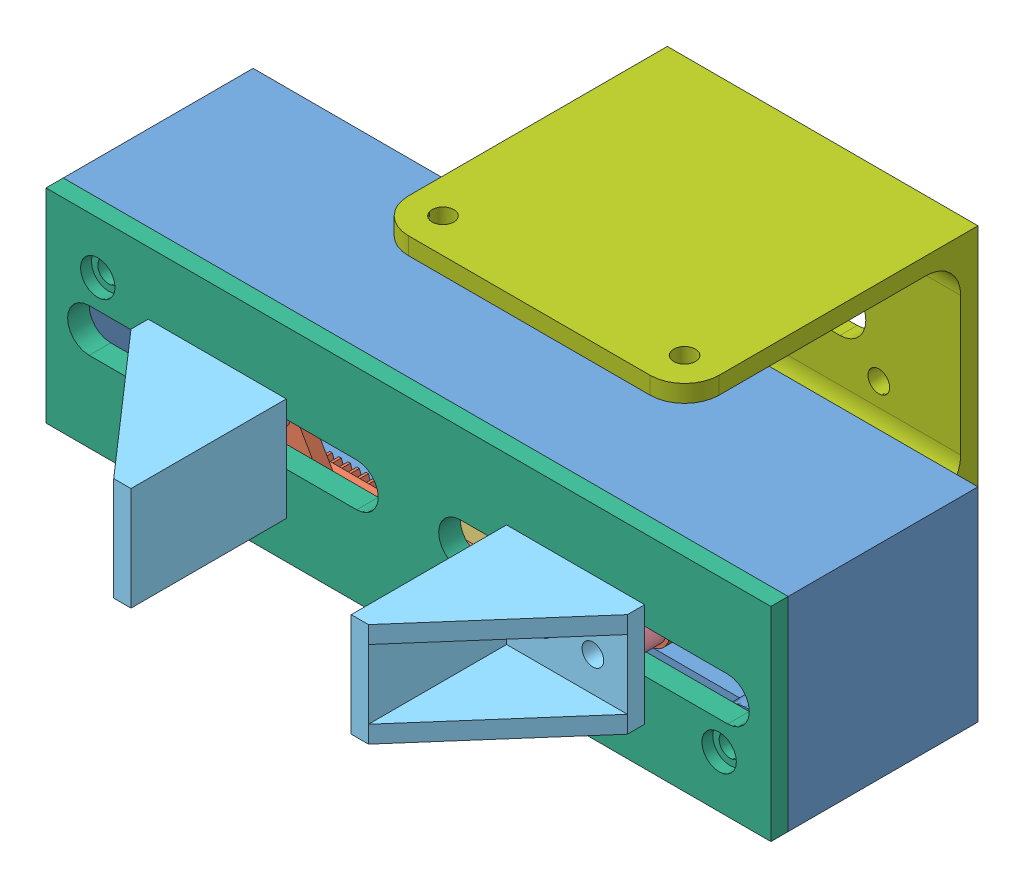
SolidWorks assembly gripper_assy, configuration Default. Lengths in mm.
Overall size (133.35 44.45 106.99).
23 component instances, 10 part files, 46 mates.
Components (placement in the parent):
- base_1-1: base_1 [Default] at origin size (133.35 37.46 34.92)
- claw_rack-1: claw_rack [2662N54] at (-13.7465 -13.97 25.2313) x (-1 0 0) z (0 0 -1) size (58.74 19.28 10.32)
- claw_rack-2: claw_rack [2662N54] at (13.7547 13.97 25.2313) x (1 0 0) z (0 0 -1) size (58.74 19.28 10.32)
- driving_gear-1: driving_gear [2662N25] at (0 0 26.025) x (0.416667 -0.909059 0) z (0 0 -1) size (26.42 26.42 9.53)
- spacer-1: spacer [Default] at (-39.3052 -0.0889 39.5188) x (-0.026879 -0.999639 0) z (0.999639 -0.026879 0) size (6.35 6.35 6.35)
- spacer-2: spacer [Default] at (-29.7802 -0.0889 39.5188) x (0.347452 -0.937698 0) z (0.937698 0.347452 0) size (6.35 6.35 6.35)
- spacer-3: spacer [Default] at (29.7884 0.0889 39.5188) x (1 0 0) z (0 1 0) size (6.35 6.35 6.35)
- spacer-4: spacer [Default] at (39.3134 0.0889 39.5188) x (1 0 0) z (0 1 0) size (6.35 6.35 6.35)
- claw_tip-1: claw_tip [Default] at (-20.2552 -0.0889 40.3125) size (25.4 19.05 28.57)
- claw_tip-2: claw_tip [Default] at (20.2634 0.0889 40.3125) x (-1 0 0) z (0 0 1) size (25.4 19.05 28.57)
- base_2-1: base_2 [Default] at (0 0 38.1) x (1 0 0) z (0 1 0) size (133.35 3.97 37.46)
- adaptor-1: adaptor [Default] at (0 0 -38.1) size (57.15 44.45 53.98)
- washer-1: washer [Default] at (-39.3052 -0.0889 39.5188) x (0.921267 0.388931 0) z (0.388931 -0.921267 0) size (7.94 0.4 7.94)
- washer-2: washer [Default] at (-29.7802 -0.0889 39.5188) x (0.804284 -0.594245 0) z (-0.594245 -0.804284 0) size (7.94 0.4 7.94)
- washer-3: washer [Default] at (29.7884 0.0889 39.5188) x (0.466217 0.88467 0) z (0.88467 -0.466217 0) size (7.94 0.4 7.94)
- washer-4: washer [Default] at (39.3134 0.0889 39.5188) x (0.481944 0.876202 0) z (0.876202 -0.481944 0) size (7.94 0.4 7.94)
- washer-9: washer [Default] at (39.3134 0.0889 39.9156) x (0.481944 0.876202 0) z (0.876202 -0.481944 0) size (7.94 0.4 7.94)
- washer-10: washer [Default] at (29.7884 0.0889 39.9156) x (0.466217 0.88467 0) z (0.88467 -0.466217 0) size (7.94 0.4 7.94)
- washer-11: washer [Default] at (-29.7802 -0.0889 39.9156) x (0.804284 -0.594245 0) z (-0.594245 -0.804284 0) size (7.94 0.4 7.94)
- washer-12: washer [Default] at (-39.3052 -0.0889 39.9156) x (0.921267 0.388931 0) z (0.388931 -0.921267 0) size (7.94 0.4 7.94)
- hs-422-1: hs-422 [Default] at (10.3124 0 9.7282) x (1 0 0) z (0 -1 0)
  - servo body.stp-1: servo body.stp [Default] x (1 0 0) z (0 0 -1) (suppressed, hidden)
  - servo output.stp-1: servo output.stp [Default] at (-10.3124 3.6322 0) x (0.949995 0 0.312266) z (-0.312266 0 0.949995) (suppressed, hidden)
Mates (geometry in assembly coordinates):
- Coincident1: coincident aligned: plane of base_1-1 through (0 0 0) normal (0 0 1)
- Coincident2: coincident aligned: plane of assembly through (0 0 0) normal (0 1 0); plane of base_1-1 through (0 0 0) normal (0 1 0)
- Coincident3: coincident aligned: plane of base_1-1 through (0 0 0) normal (1 0 0)
- Coincident4: coincident anti-aligned: plane of base_1-1 through (63.5 15.5575 -138.513) normal (0 -1 0); plane of claw_rack-2 through (43.1234 15.5575 22.85) normal (0 1 0)
- Coincident5: coincident anti-aligned: plane of base_1-1 through (0 0 22.85) normal (0 0 1); plane of claw_rack-2 through (43.1234 12.3825 22.85) normal (0 0 -1)
- Coincident6: coincident anti-aligned: plane of base_1-1 through (63.5 -15.5575 -138.513) normal (0 1 0); plane of claw_rack-1 through (-43.1152 -15.5575 22.85) normal (0 -1 0)
- Coincident7: coincident anti-aligned: plane of claw_rack-1 through (-43.1152 -12.3825 22.85) normal (0 0 -1); plane of base_1-1 through (0 0 22.85) normal (0 0 1)
- Coincident9: coincident aligned: plane of claw_rack-1 through (-43.1152 -12.3825 22.85) normal (0 0 -1); plane of driving_gear-1 through (-8.6588 -3.9688 22.85) normal (0 0 -1)
- Concentric1: concentric aligned: cylinder of driving_gear-1 through (0 0 22.85) axis (0 0 1) radius 1.5
- RackPinionMate1: rack pinion = 25.4 mm: line of claw_rack-2 through (43.1234 15.5575 22.85) axis (-1 0 0); circle of driving_gear-1
- RackPinionMate2: rack pinion = 25.4 mm: line of claw_rack-1 through (-43.1152 -15.5575 22.85) axis (1 0 0); circle of driving_gear-1
- Concentric3: concentric aligned: cylinder of claw_rack-1 through (-39.3052 -0.0889 30.7875) axis (0 0 1) radius 2; cylinder of spacer-1 through (-39.3052 -0.0889 39.5188) axis (0 0 1) radius 2
- Coincident10: coincident anti-aligned: plane of claw_rack-1 through (-39.9402 -12.3825 33.1688) normal (0 0 1); plane of spacer-1 through (-39.2515 1.9104 33.1688) normal (0 0 -1)
- Coincident11: coincident anti-aligned: plane of claw_rack-1 through (-39.9402 -12.3825 33.1688) normal (0 0 1); plane of spacer-2 through (-30.4751 1.7865 33.1688) normal (0 0 -1)
- Coincident12: coincident anti-aligned: plane of claw_rack-2 through (39.9484 12.3825 33.1688) normal (0 0 1); plane of spacer-3 through (27.7884 0.0889 33.1688) normal (0 0 -1)
- Coincident13: coincident anti-aligned: plane of claw_rack-2 through (39.9484 12.3825 33.1688) normal (0 0 1); plane of spacer-4 through (37.3134 0.0889 33.1688) normal (0 0 -1)
- Concentric4: concentric aligned: cylinder of claw_rack-2 through (39.3134 0.0889 30.7875) axis (0 0 1) radius 2; cylinder of spacer-4 through (39.3134 0.0889 39.5188) axis (0 0 1) radius 2
- Concentric5: concentric aligned: cylinder of claw_rack-2 through (29.7884 0.0889 30.7875) axis (0 0 1) radius 2; cylinder of spacer-3 through (29.7884 0.0889 39.5188) axis (0 0 1) radius 2
- Concentric6: concentric aligned: cylinder of claw_rack-1 through (-29.7802 -0.0889 30.7875) axis (0 0 1) radius 2; cylinder of spacer-2 through (-29.7802 -0.0889 39.5188) axis (0 0 1) radius 2
- Concentric7: concentric anti-aligned: cylinder of spacer-2 through (-29.7802 -0.0889 39.5188) axis (0 0 1) radius 2; cylinder of claw_tip-1 through (-29.7802 -0.0889 43.4875) axis (0 0 -1) radius 2
- Concentric8: concentric anti-aligned: cylinder of spacer-1 through (-39.3052 -0.0889 39.5188) axis (0 0 1) radius 2; cylinder of claw_tip-1 through (-39.3052 -0.0889 43.4875) axis (0 0 -1) radius 2
- Concentric9: concentric anti-aligned: cylinder of spacer-3 through (29.7884 0.0889 39.5188) axis (0 0 1) radius 2; cylinder of claw_tip-2 through (29.7884 0.0889 43.4875) axis (0 0 -1) radius 2
- Concentric10: concentric anti-aligned: cylinder of spacer-4 through (39.3134 0.0889 39.5188) axis (0 0 1) radius 2; cylinder of claw_tip-2 through (39.3134 0.0889 43.4875) axis (0 0 -1) radius 2
- LimitDistance1: limit distance = 40.5187 mm anti-aligned: plane of claw_tip-1 through (-20.2552 9.4361 43.4875) normal (1 0 0); plane of claw_tip-2 through (20.2634 -9.4361 43.4875) normal (-1 0 0)
- Coincident18: coincident anti-aligned: plane of base_1-1 through (0 0 34.925) normal (0 0 1); plane of base_2-1 through (0 0 34.925) normal (0 0 -1)
- Concentric11: concentric aligned: cylinder of base_1-1 through (57.15 -9.2075 -0.001) axis (0 0 1) radius 2; cylinder of base_2-1 through (57.15 -9.2075 36.1) axis (0 0 1) radius 3.175
- Concentric12: concentric aligned: cylinder of base_1-1 through (-57.15 9.2075 -0.001) axis (0 0 1) radius 2; cylinder of base_2-1 through (-57.15 9.2075 36.1) axis (0 0 1) radius 3.175
- Coincident19: coincident aligned: plane of base_1-1 through (0 0 0) normal (0 1 0); plane of adaptor-1 through (0 0 -38.1) normal (0 1 0)
- Concentric13: concentric anti-aligned: cylinder of base_1-1 through (-22.225 -18.7325 9.525) axis (0 1 0) radius 2; cylinder of adaptor-1 through (-22.225 22.226 9.525) axis (0 -1 0) radius 2
- Concentric14: concentric anti-aligned: cylinder of base_1-1 through (22.225 -18.7325 9.525) axis (0 1 0) radius 2; cylinder of adaptor-1 through (22.225 22.226 9.525) axis (0 -1 0) radius 2
- Concentric15: concentric anti-aligned: cylinder of spacer-1 through (-39.3052 -0.0889 39.5188) axis (0 0 1) radius 2; cylinder of washer-1 through (-39.3052 -0.0889 39.5188) axis (0 0 -1) radius 2.3813
- Concentric16: concentric anti-aligned: cylinder of spacer-2 through (-29.7802 -0.0889 39.5188) axis (0 0 1) radius 2; cylinder of washer-2 through (-29.7802 -0.0889 39.5188) axis (0 0 -1) radius 2.3813
- Coincident21: coincident anti-aligned: plane of spacer-1 through (-39.2515 1.9104 39.5188) normal (0 0 1); plane of washer-1 through (-41.499 -1.015 39.5188) normal (0 0 -1)
- Coincident22: coincident anti-aligned: plane of spacer-2 through (-30.4751 1.7865 39.5188) normal (0 0 1); plane of washer-2 through (-31.6954 1.3261 39.5188) normal (0 0 -1)
- Concentric17: concentric anti-aligned: cylinder of spacer-3 through (29.7884 0.0889 39.5188) axis (0 0 1) radius 2; cylinder of washer-3 through (29.7884 0.0889 39.5188) axis (0 0 -1) radius 2.3813
- Coincident23: coincident anti-aligned: plane of spacer-3 through (27.7884 0.0889 39.5188) normal (0 0 1); plane of washer-3 through (28.6783 -2.0177 39.5188) normal (0 0 -1)
- Concentric18: concentric anti-aligned: cylinder of spacer-4 through (39.3134 0.0889 39.5188) axis (0 0 1) radius 2; cylinder of washer-4 through (39.3134 0.0889 39.5188) axis (0 0 -1) radius 2.3813
- Coincident24: coincident anti-aligned: plane of spacer-4 through (37.3134 0.0889 39.5188) normal (0 0 1); plane of washer-4 through (38.1658 -1.9976 39.5188) normal (0 0 -1)
- Coincident25: coincident anti-aligned: plane of claw_tip-1 through (-20.2552 -0.0889 40.3125) normal (0 0 -1); plane of washer-12 through (-41.499 -1.015 40.3125) normal (0 0 1)
- Coincident26: coincident anti-aligned: plane of claw_tip-2 through (20.2634 0.0889 40.3125) normal (0 0 -1); plane of washer-9 through (38.1658 -1.9976 40.3125) normal (0 0 1)
- Concentric22: concentric aligned: cylinder of hs-422.stp-3/servo body.stp-1 through (35.2 5 5.5118) axis (0 0 1) radius 2.1844; cylinder of base_1-1 through (35.2 5 -0.001) axis (0 0 1) radius 2
- Parallel6: parallel anti-aligned: plane of base_1-1 through (-10 10.5 -0.001) normal (0 -1 0); plane of hs-422.stp-3/servo body.stp-1 through (-9.25 9.9403 9.7282) normal (0 1 0)
- Coincident33: coincident anti-aligned: plane of base_1-1 through (0 0 3.175) normal (0 0 1); plane of hs-422.stp-3/servo body.stp-1 through (31.39 9.4958 3.175) normal (0 0 -1)
- Concentric23: concentric: cylinder of driving_gear-1 through (0 0 22.85) axis (0 0 1) radius 1.5; cylinder of hs-422-1/servo output.stp-1 through (0 0 13.3604) axis (0 0 1) radius 1.5
- Parallel7: parallel: plane of base_1-1 through (-10 10.5 -0.001) normal (0 -1 0); plane of hs-422-1/servo body.stp-1 through (-10.0076 9.8425 9.7282) normal (0 1 0)
- Coincident35: coincident anti-aligned: plane of base_1-1 through (0 0 3.175) normal (0 0 1); plane of hs-422-1/servo body.stp-1 through (30.6324 9.398 3.175) normal (0 0 -1)
